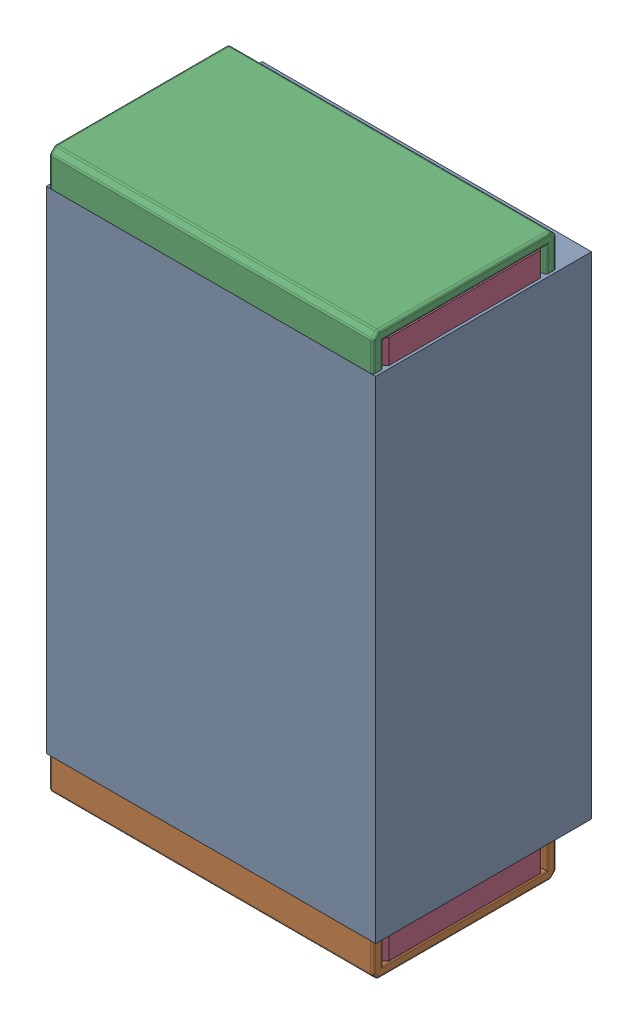
SolidWorks assembly R20, configuration Default. Lengths in mm.
Overall size (0.61 1.04 0.4).
3 component instances, 2 part files, 0 mates.
Components (placement in the parent):
- 1088881848-1: 1088881848 [Default] at (6.15 44.225 -2.044) size (0.61 0.91 0.4)
  - Extruded-1-1: Extruded-1 [Default] at origin size (0.61 0.91 0.4)
- R0402-1: R0402 [Default] at (6.1499 44.225 -1.644) x (0 -1 0) z (1 0 0) size (1.04 0.34 0.6)
